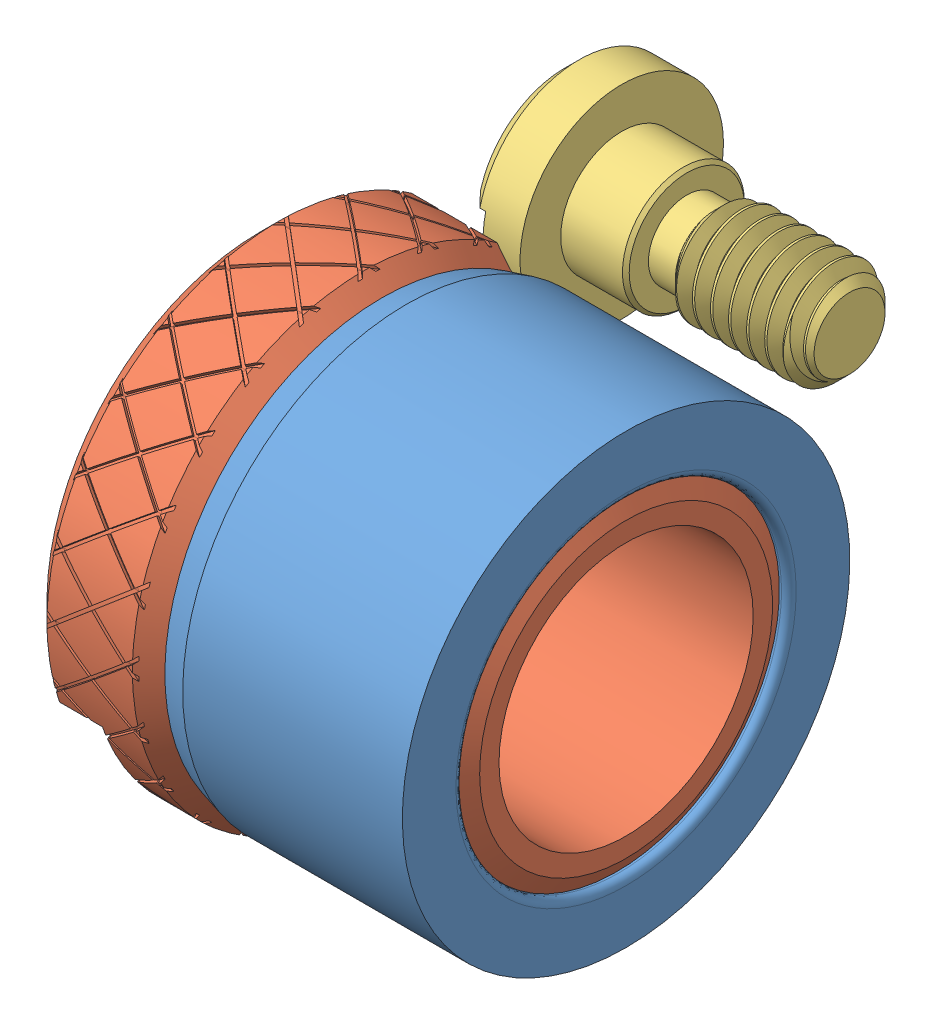
SolidWorks assembly 16 mm Bushing, configuration Default. Lengths in mm.
Overall size (28.57 50.05 51.94).
3 component instances, 3 part files, 4 mates.
Components (placement in the parent):
- 3556N198_Sleeve for Removable Drill Bushing-1: 3556N198_Sleeve for Removable Drill Bushing [3556N198] at (-5.0577 19.8409 35.2587)
- 8493A272_Removable Drill Bushing-1: 8493A272_Removable Drill Bushing [8493A272] at (-9.8202 19.8409 35.2587) x (1 0 0) z (0 0.79912 0.601171)
- 8496A15_Lock Screw for Removable Drill Bushings-1: 8496A15_Lock Screw for Removable Drill Bushings [8496A15] at (-7.9152 33.9177 16.5468)
Mates (geometry in assembly coordinates):
- Concentric1: concentric aligned: cylinder of 3556N198_Sleeve for Removable Drill Bushing-1 through (-14.5827 19.8409 35.2587) axis (-1 0 0) radius 17.4625; cylinder of 8493A272_Removable Drill Bushing-1 through (-24.1077 19.8409 35.2587) axis (-1 0 0) radius 12.7
- Coincident1: coincident anti-aligned: plane of 3556N198_Sleeve for Removable Drill Bushing-1 through (-14.5827 36.793 35.2587) normal (-1 0 0); plane of 8493A272_Removable Drill Bushing-1 through (-14.5827 30.6967 20.8284) normal (1 0 0)
- Concentric2: concentric anti-aligned: cylinder of 8493A272_Removable Drill Bushing-1 through (8.9905 33.9177 16.5468) axis (-1 0 0) radius 8.3344; cylinder of 8496A15_Lock Screw for Removable Drill Bushings-1 through (-19.0277 33.9177 16.5468) axis (1 0 0) radius 7.9375
- Coincident2: coincident anti-aligned: plane of 3556N198_Sleeve for Removable Drill Bushing-1 through (-14.5827 36.793 35.2587) normal (-1 0 0); plane of 8496A15_Lock Screw for Removable Drill Bushings-1 through (-14.5827 33.9177 16.5468) normal (1 0 0)
